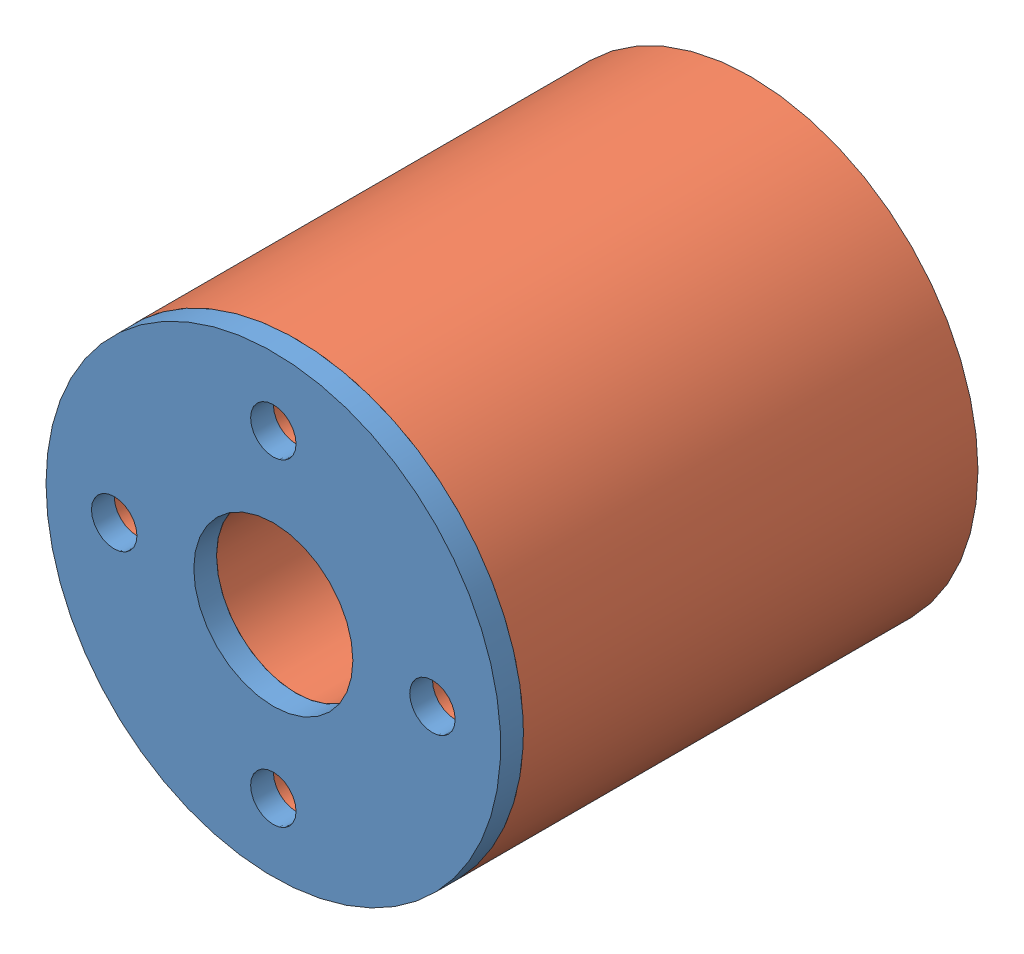
SolidWorks assembly snake_unit, configuration ﾃﾞﾌｫﾙﾄ. Lengths in mm.
Overall size (12 12 21).
2 component instances, 2 part files, 3 mates.
Components (placement in the parent):
- plate-1: plate [ﾃﾞﾌｫﾙﾄ] at (-3.9039 0.4237 19.5) size (12 12 1)
- sponge-1: sponge [ﾃﾞﾌｫﾙﾄ] at (-3.9039 0.4237 -0.5) size (12 12 20)
Mates (geometry in assembly coordinates):
- 一致1: coincident: plane of plate-1 through (-3.9039 0.4237 19.5) normal (0 0 -1); plane of sponge-1 through (-3.9039 0.4237 19.5) normal (0 0 1)
- 同心円2: concentric: cylinder of plate-1 through (-3.9039 3.4237 20.5) axis (0 0 -1) radius 1; cylinder of sponge-1 through (-3.9039 3.4237 19.5) axis (0 0 -1) radius 1
- 同心円3: concentric: circle of plate-1; cylinder of sponge-1 through (-3.9039 -2.5763 19.5) axis (0 0 -1) radius 1
